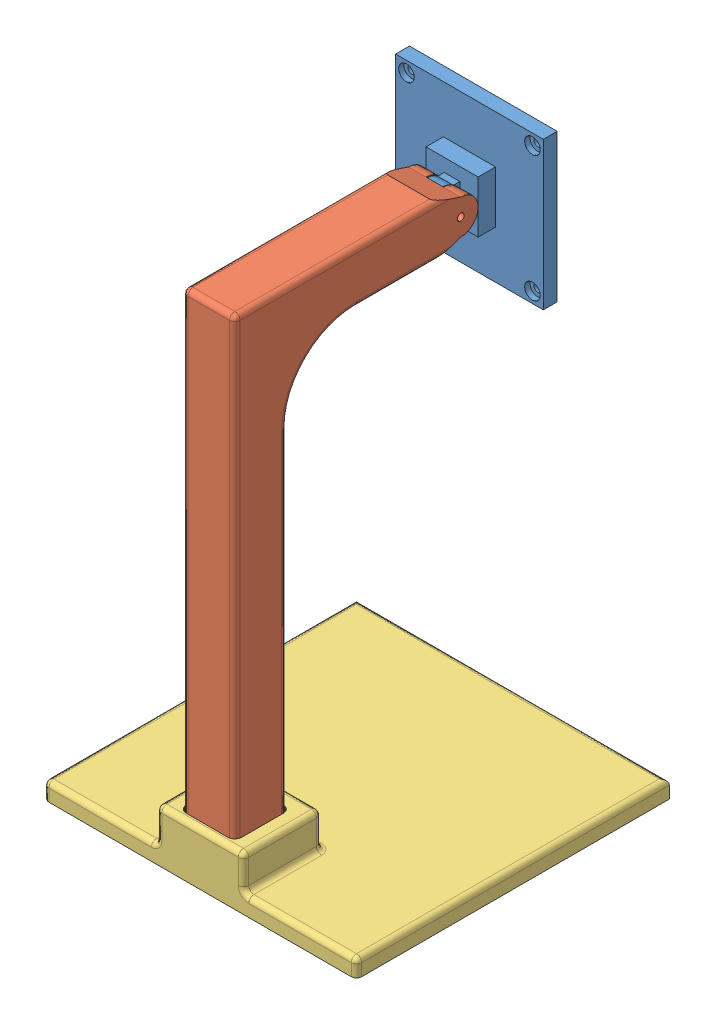
SolidWorks assembly Montagem, configuration Default. Lengths in mm.
Overall size (180 317.5 180).
3 component instances, 3 part files, 7 mates.
Components (placement in the parent):
- SuporteMonitor-1: SuporteMonitor [Default] at (-25.0702 49.169 77.9478) size (85 85 37.75)
- braço^Montagem-1: braço^Montagem [Default] at (-25.0702 49.169 105.9478) size (30 280 140) (virtual)
- Base^Montagem-1: Base^Montagem [Default] at (-25.0702 -215.831 105.9478) x (-1 0 0) z (0 -1 0) size (180 180 30) (virtual)
Mates (geometry in assembly coordinates):
- Concêntrico1: concentric anti-aligned: cylinder of SuporteMonitor-1 through (-20.5702 49.169 105.9478) axis (-1 0 0) radius 9.75; cylinder of braço^Montagem-1 through (-30.0702 49.169 105.9478) axis (1 0 0) radius 10
- Coincidente5: coincident aligned: plane of SuporteMonitor-1 through (-40.0702 64.169 105.9478) normal (-1 0 0); plane of braço^Montagem-1 through (-40.0702 64.169 135.9478) normal (-1 0 0)
- Paralelo1: parallel aligned: plane of SuporteMonitor-1 through (-40.0702 64.169 105.9478) normal (0 1 0); plane of braço^Montagem-1 through (-10.0702 64.169 135.9478) normal (0 1 0)
- No local2: in place: plane of braço^Montagem-1 through (-25.0702 -265.831 105.9478) normal (0 -1 0); plane of ? through (0 -265.831 0) normal (0 -1 0); moOrthogonalPlaneRef_w of braço^Montagem-1 through (-25.0702 -265.831 105.9478) normal (0 -1 0); plane of ? through (0 -265.831 0) normal (0 0 -1); plane of braço^Montagem-1 through (-25.0702 -265.831 105.9478) normal (0 -1 0); plane of ? through (0 -265.831 0) normal (-1 0 0); plane of braço^Montagem-1 through (-25.0702 -215.831 105.9478) normal (0 -1 0); unknown of Base^Montagem-1
- Coincidente6: coincident aligned: plane of braço^Montagem-1 through (-25.0702 -215.831 105.9478) normal (0 -1 0); plane of Base^Montagem-1 through (-25.0702 -215.831 105.9478) normal (0 -1 0)
- Coincidente7: coincident aligned: moOrthogonalPlaneRef_w of braço^Montagem-1 through (-25.0702 -215.831 105.9478) normal (0 0 -1); plane of Base^Montagem-1 through (-25.0702 -215.831 105.9478) normal (0 0 -1)
- Coincidente8: coincident anti-aligned: moOrthogonalPlaneRef_w of braço^Montagem-1 through (-25.0702 -215.831 105.9478) normal (1 0 0); plane of Base^Montagem-1 through (-25.0702 -215.831 105.9478) normal (-1 0 0)
